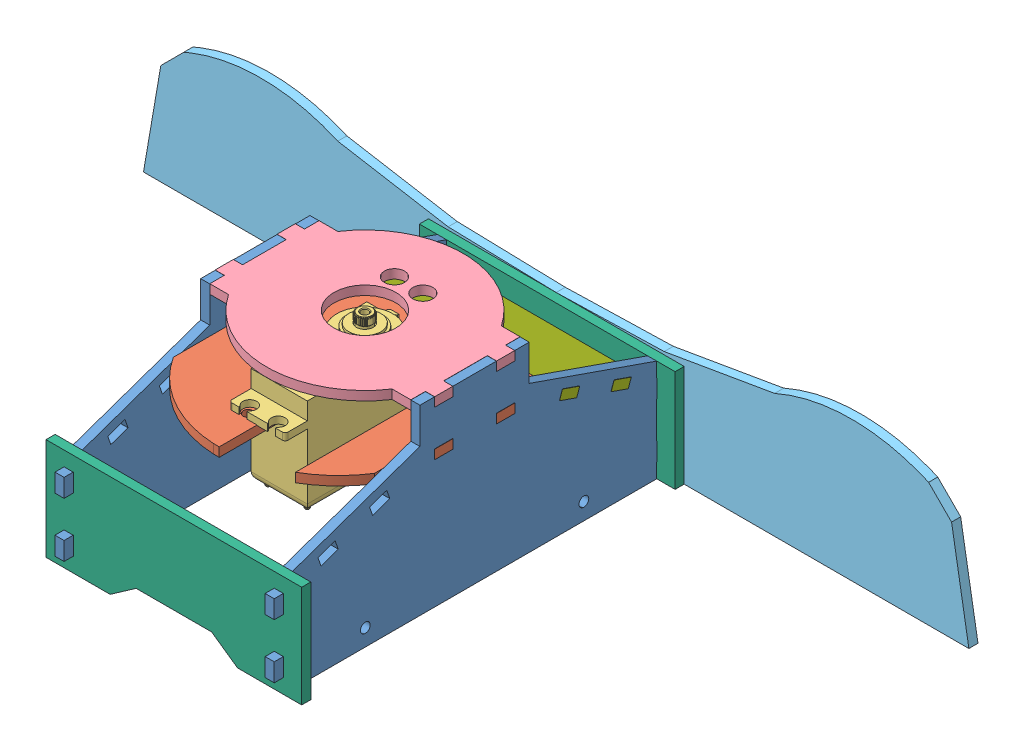
SolidWorks assembly assemblyRotateBase, configuration Default. Lengths in mm.
Overall size (287.78 63.55 136.53).
10 component instances, 7 part files, 26 mates.
Components (placement in the parent):
- rotateBaseSides-1: rotateBaseSides [Default] at (8.1657 0.2779 -4.4977) size (3.18 63.5 136.53)
- rotateBaseSides-2: rotateBaseSides [Default] at (-65.1133 0.2779 -4.4977) size (3.18 63.5 136.53)
- rotateBaseServoPlate-1: rotateBaseServoPlate [Default] at (-26.8863 13.0541 -4.4977) size (76.56 3.18 76.2)
- Standard ServoB-1: Standard ServoB [Default] at (-25.2626 -10.8409 6.7516) x (0 0 -1) z (1 0 0) size (55.73 42.63 19.57)
- thrustBearingBottom-1: thrustBearingBottom [Default] at (-26.8863 28.9037 -4.4977) size (76.56 3.18 68.58)
- shoulderFront-1: shoulderFront [Default] at (-26.8355 -31.4721 -74.3477) size (143.94 48.97 3.17)
- shoulderFront-2: shoulderFront [Default] at (-26.9371 -31.4721 -71.1727) x (-1 0 0) z (0 0 -1) size (143.94 48.97 3.17)
- chestWall-1: chestWall [Default] at (-26.8355 -13.6921 -71.1727) size (89.15 35.56 3.17)
- chestWall-2: chestWall [Default] at (-26.8355 -13.6921 59.0023) size (89.15 35.56 3.17)
- neckCover-1: neckCover [Default] at (-26.8863 4.9145 -46.0534) x (1 0 0) z (0 0.328989 0.944334) size (76.56 3.18 31.75)
Mates (geometry in assembly coordinates):
- Coincident4: coincident anti-aligned: plane of rotateBaseSides-1 through (11.3407 13.0541 3.1223) normal (0 1 0); plane of rotateBaseServoPlate-1 through (8.1657 13.0541 -29.8977) normal (0 -1 0)
- Coincident5: coincident anti-aligned: plane of rotateBaseSides-1 through (11.3407 16.2799 9.4723) normal (0 0 -1); plane of rotateBaseServoPlate-1 through (8.1657 13.0541 9.4723) normal (0 0 1)
- Coincident6: coincident anti-aligned: plane of rotateBaseSides-1 through (8.1657 32.0279 -23.5477) normal (-1 0 0); plane of rotateBaseServoPlate-1 through (8.1657 16.2291 20.9023) normal (1 0 0)
- Coincident7: coincident anti-aligned: plane of rotateBaseSides-2 through (-61.9383 13.0541 3.1223) normal (0 1 0); plane of rotateBaseServoPlate-1 through (8.1657 13.0541 -29.8977) normal (0 -1 0)
- Coincident8: coincident anti-aligned: plane of rotateBaseSides-2 through (-61.9383 16.2799 9.4723) normal (0 0 -1); plane of rotateBaseServoPlate-1 through (-61.9383 13.0541 9.4723) normal (0 0 1)
- Coincident9: coincident anti-aligned: plane of rotateBaseSides-2 through (-61.9383 32.0279 -23.5477) normal (1 0 0); plane of rotateBaseServoPlate-1 through (-61.9383 16.2291 20.9023) normal (-1 0 0)
- Coincident13: coincident anti-aligned: plane of rotateBaseSides-1 through (11.3407 28.9037 3.1223) normal (0 1 0); plane of thrustBearingBottom-1 through (8.1657 28.9037 -23.5477) normal (0 -1 0)
- Coincident14: coincident anti-aligned: plane of rotateBaseSides-1 through (11.3407 32.0279 9.4723) normal (0 0 -1); plane of thrustBearingBottom-1 through (8.1657 28.9037 9.4723) normal (0 0 1)
- Coincident15: coincident anti-aligned: plane of rotateBaseSides-1 through (8.1657 32.0279 -23.5477) normal (-1 0 0); plane of thrustBearingBottom-1 through (8.1657 32.0787 14.5523) normal (1 0 0)
- Coincident22: coincident anti-aligned: plane of rotateBaseSides-1 through (8.1657 -26.3921 -67.9977) normal (0 -1 0); plane of chestWall-1 through (11.3915 -26.3921 -71.1727) normal (0 1 0)
- Coincident23: coincident anti-aligned: plane of rotateBaseSides-1 through (8.1657 32.0279 -23.5477) normal (-1 0 0); plane of chestWall-1 through (8.1657 -20.0421 -71.1727) normal (1 0 0)
- Coincident24: coincident anti-aligned: plane of rotateBaseSides-1 through (11.3407 -31.4721 -67.9977) normal (0 0 -1); plane of chestWall-1 through (17.7415 4.0879 -67.9977) normal (0 0 1)
- Coincident25: coincident anti-aligned: plane of rotateBaseSides-1 through (11.3407 32.0279 -23.5477) normal (1 0 0); plane of shoulderFront-2 through (11.3407 -0.9921 -71.1727) normal (-1 0 0)
- Coincident26: coincident anti-aligned: plane of rotateBaseSides-1 through (8.1657 -7.3421 -67.9977) normal (0 -1 0); plane of shoulderFront-2 through (11.3407 -7.3421 -71.1727) normal (0 1 0)
- Coincident27: coincident anti-aligned: plane of shoulderFront-2 through (76.1039 17.3839 -71.1727) normal (0 0 1); plane of chestWall-1 through (17.7415 4.0879 -71.1727) normal (0 0 -1)
- Coincident28: coincident anti-aligned: plane of rotateBaseSides-2 through (-65.1133 -26.3921 -67.9977) normal (0 -1 0); plane of shoulderFront-1 through (-65.1133 -26.3921 -74.3477) normal (0 1 0)
- Coincident30: coincident anti-aligned: plane of shoulderFront-1 through (-129.8766 17.3839 -71.1727) normal (0 0 1); plane of chestWall-1 through (17.7415 4.0879 -71.1727) normal (0 0 -1)
- Coincident31: coincident anti-aligned: plane of rotateBaseSides-2 through (-65.1133 32.0279 -23.5477) normal (-1 0 0); plane of shoulderFront-1 through (-65.1133 -0.9921 -74.3477) normal (1 0 0)
- Coincident38: coincident anti-aligned: plane of rotateBaseSides-1 through (8.1657 32.0279 -23.5477) normal (-1 0 0); plane of chestWall-2 through (8.1657 -0.9921 59.0023) normal (1 0 0)
- Coincident40: coincident anti-aligned: plane of rotateBaseSides-1 through (11.3407 -31.4721 59.0023) normal (0 0 1); plane of chestWall-2 through (17.7415 4.0879 59.0023) normal (0 0 -1)
- Coincident41: coincident anti-aligned: plane of rotateBaseSides-1 through (8.1657 -26.3921 59.0023) normal (0 -1 0); plane of chestWall-2 through (11.3915 -26.3921 59.0023) normal (0 1 0)
- Coincident43: coincident anti-aligned: plane of rotateBaseServoPlate-1 through (-16.5933 13.0541 -14.9117) normal (0 0 1); plane of Standard ServoB-1 through (-36.6419 24.5291 -14.9117) normal (0 0 -1)
- Coincident44: coincident anti-aligned: plane of rotateBaseServoPlate-1 through (8.1657 16.2291 -29.8977) normal (0 1 0); plane of Standard ServoB-1 through (-36.6419 16.2291 -22.6117) normal (0 -1 0)
- Coincident45: coincident anti-aligned: plane of rotateBaseSides-2 through (-61.9383 9.0926 -34.0604) normal (0 0.944334 -0.328989); plane of neckCover-1 through (8.1657 -0.3082 -61.0447) normal (0 -0.944334 0.328989)
- Coincident46: coincident anti-aligned: plane of rotateBaseSides-2 through (-61.9383 7.0036 -40.0569) normal (0 0.328989 0.944334); plane of neckCover-1 through (-61.9383 7.0036 -40.0569) normal (0 -0.328989 -0.944334)
- Coincident47: coincident anti-aligned: plane of rotateBaseSides-2 through (-61.9383 32.0279 -23.5477) normal (1 0 0); plane of neckCover-1 through (-61.9383 13.1354 -32.1067) normal (-1 0 0)
